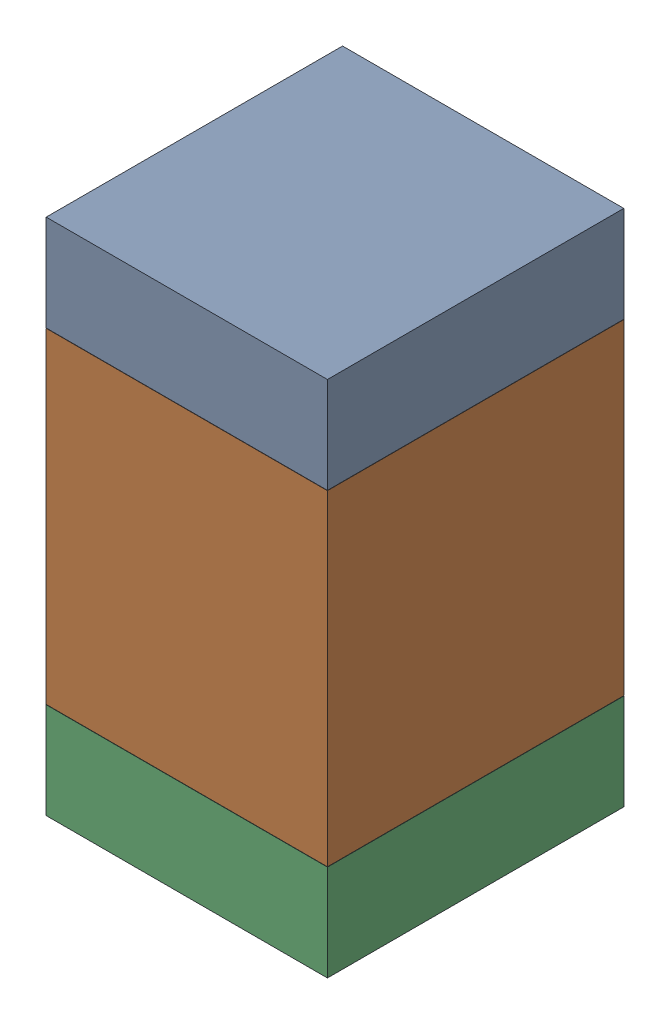
SolidWorks assembly R21, configuration Default. Lengths in mm.
Overall size (0.95 1.75 1).
6 component instances, 2 part files, 0 mates.
Components (placement in the parent):
- 6575495072-1: 6575495072 [Default] at (11.049 19.1275 0) size (0.95 0.32 1)
  - Extruded_6-1: Extruded_6 [Default] at origin size (0.95 0.32 1)
- 6575494912-1: 6575494912 [Default] at (11.049 18.415 0) size (0.95 1.1 1)
  - Extruded_7-1: Extruded_7 [Default] at origin size (0.95 1.1 1)
- 6575495072-2: 6575495072 [Default] at (11.049 17.7025 0) size (0.95 0.32 1)
  - Extruded_6-1: Extruded_6 [Default] at origin size (0.95 0.32 1)
